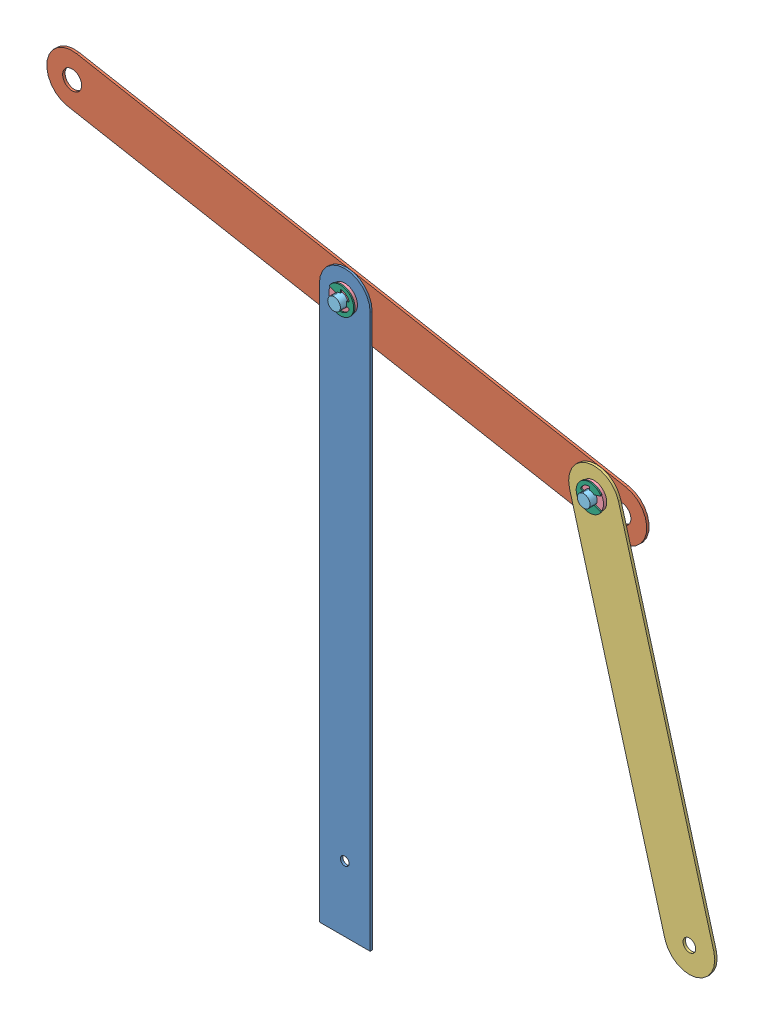
SolidWorks assembly Linkages Assembly, configuration Default. Lengths in mm.
Overall size (327.98 314.55 12.7).
11 component instances, 6 part files, 20 mates.
Components (placement in the parent):
- Fulcrum Support-1: Fulcrum Support [Default] at (116.1068 141.0237 228.2309) size (25.4 289.56 1.2)
- Fulcrum Linkage-1: Fulcrum Linkage [Default] at (116.1068 279.4537 227.2309) x (0.983599 -0.180367 0) z (0 0 1) size (304.8 25.4 1.2)
- Disc-Fulcrum Connecting Linkage-1: Disc-Fulcrum Connecting Linkage [Default] at (264.8821 170.9083 228.4309) x (0.963315 0.268371 0) z (0 0 1) size (25.4 203.2 1.2)
- Sleeve Bearing-1: Sleeve Bearing [1677K316] at (116.1068 279.4537 231.0184) x (1 0 0) z (0 1 0) size (12.7 4.76 12.7)
- Sleeve Bearing-2: Sleeve Bearing [1677K316] at (241.0239 256.547 231.2184) x (1 0 0) z (0 1 0) size (12.7 4.76 12.7)
- Shaft (0.25 length)-1: Shaft (0.25 length) [Default] at (241.0239 256.547 222.0809) x (0.96153 0.2747 0) z (0 0 1) size (6.35 6.35 12.7)
- Shaft (0.25 length)-2: Shaft (0.25 length) [Default] at (116.1068 279.4537 222.0809) size (6.35 6.35 12.7)
- E-Clips-1: E-Clips [97431A300] at (241.0239 256.547 231.5359) x (0 0 -1) z (1 0 0) size (0.64 13.39 12.2)
- E-Clips-2: E-Clips [97431A300] at (241.0239 256.547 226.1384) x (0 0 1) z (-1 0 0) size (0.64 13.39 12.2)
- E-Clips-3: E-Clips [97431A300] at (116.1068 279.4537 231.3359) x (0 0 1) z (-1 0 0) size (0.64 13.39 12.2)
- E-Clips-4: E-Clips [97431A300] at (116.1068 279.4537 225.9384) x (0 0 1) z (-1 0 0) size (0.64 13.39 12.2)
Mates (geometry in assembly coordinates):
- Coincident1: coincident anti-aligned: plane of Fulcrum Support-1 through (116.1068 141.0237 229.4309) normal (0 0 1); plane of Sleeve Bearing-1 through (116.1068 279.4537 229.4309) normal (0 0 -1)
- Concentric1: concentric anti-aligned: circle of Fulcrum Support-1; circle of Sleeve Bearing-1
- Concentric2: concentric anti-aligned: circle of Fulcrum Linkage-1; circle of Sleeve Bearing-1
- Coincident5: coincident anti-aligned: plane of Fulcrum Linkage-1 through (116.1068 279.4537 228.4309) normal (0 0 1); plane of Disc-Fulcrum Connecting Linkage-1 through (264.8821 170.9083 228.4309) normal (0 0 -1)
- Concentric5: concentric aligned: circle of Fulcrum Linkage-1; circle of Disc-Fulcrum Connecting Linkage-1
- Concentric6: concentric anti-aligned: circle of Disc-Fulcrum Connecting Linkage-1; circle of Sleeve Bearing-2
- Coincident7: coincident anti-aligned: plane of Disc-Fulcrum Connecting Linkage-1 through (264.8821 170.9083 229.6309) normal (0 0 1); plane of Sleeve Bearing-2 through (241.0239 256.547 229.6309) normal (0 0 -1)
- Concentric7: concentric anti-aligned: cylinder of Sleeve Bearing-1 through (116.1068 279.4537 226.2559) axis (0 0 1) radius 3.1877; cylinder of Shaft (0.25 length)-2 through (116.1068 279.4537 234.7809) axis (0 0 -1) radius 3.175
- Concentric8: concentric anti-aligned: cylinder of Sleeve Bearing-2 through (241.0239 256.547 226.4559) axis (0 0 1) radius 3.1877; cylinder of Shaft (0.25 length)-1 through (241.0239 256.547 234.7809) axis (0 0 -1) radius 3.175
- Distance2: distance = 6.35 mm: plane of Shaft (0.25 length)-2 through (116.1068 279.4537 234.7809) normal (0 0 1); line of Fulcrum Linkage-1 through (-6.5196 314.8521 228.4309) axis (0.983599 -0.180367 0)
- Distance3: distance = 6.35 mm aligned: plane of Shaft (0.25 length)-1 through (241.0239 256.547 234.7809) normal (0 0 1); plane of Fulcrum Linkage-1 through (116.1068 279.4537 228.4309) normal (0 0 1)
- Coincident11: coincident anti-aligned: plane of Sleeve Bearing-2 through (241.0239 256.547 231.2184) normal (0 0 1); plane of E-Clips-1 through (241.0239 256.547 231.2184) normal (0 0 -1)
- Concentric11: concentric aligned: circle of Shaft (0.25 length)-1; circle of E-Clips-1
- Coincident12: coincident anti-aligned: plane of Sleeve Bearing-2 through (241.0239 256.547 226.4559) normal (0 0 -1); plane of E-Clips-2 through (241.0239 256.547 226.4559) normal (0 0 1)
- Concentric12: concentric anti-aligned: circle of Shaft (0.25 length)-1; circle of E-Clips-2
- Coincident13: coincident anti-aligned: plane of Sleeve Bearing-1 through (116.1068 279.4537 226.2559) normal (0 0 -1); plane of E-Clips-4 through (116.1068 279.4537 226.2559) normal (0 0 1)
- Concentric13: concentric anti-aligned: circle of Shaft (0.25 length)-2; circle of E-Clips-4
- Coincident14: coincident anti-aligned: plane of Sleeve Bearing-1 through (116.1068 279.4537 231.0184) normal (0 0 1); plane of E-Clips-3 through (116.1068 279.4537 231.0184) normal (0 0 -1)
- Concentric14: concentric anti-aligned: circle of Shaft (0.25 length)-2; circle of E-Clips-3
- Distance4: distance = 1 mm aligned: plane of Fulcrum Linkage-1 through (116.1068 279.4537 227.2309) normal (0 0 -1); plane of Fulcrum Support-1 through (116.1068 141.0237 228.2309) normal (0 0 -1)
